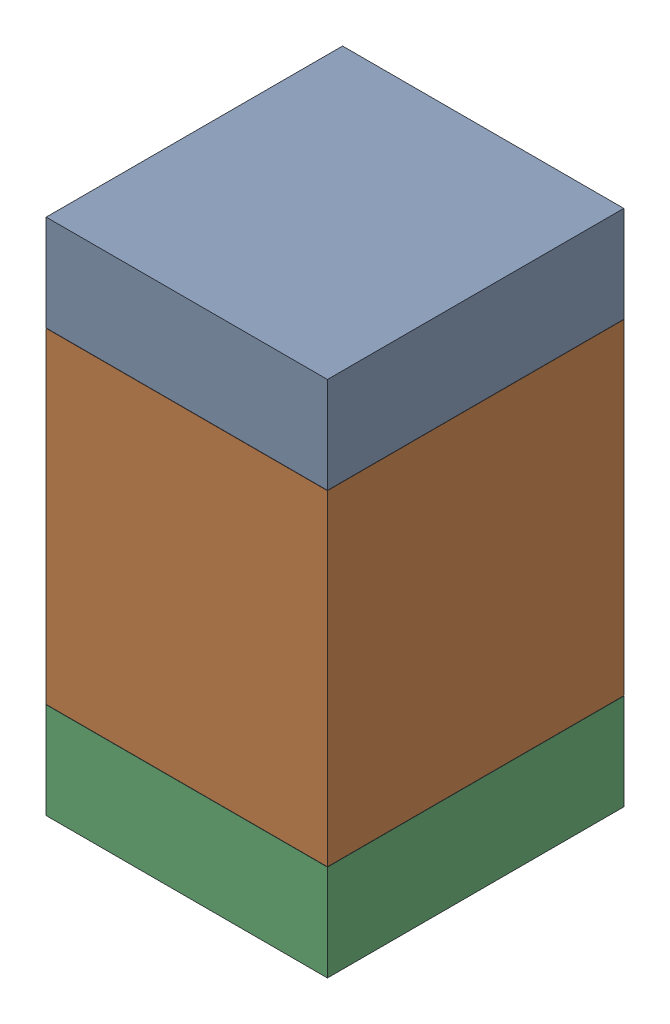
SolidWorks assembly R30, configuration Default. Lengths in mm.
Overall size (0.95 1.75 1).
6 component instances, 2 part files, 0 mates.
Components (placement in the parent):
- 6575495072-1: 6575495072 [Default] at (44.831 6.8085 0) size (0.95 0.32 1)
  - Extruded_6-1: Extruded_6 [Default] at origin size (0.95 0.32 1)
- 6575494912-1: 6575494912 [Default] at (44.831 6.096 0) size (0.95 1.1 1)
  - Extruded_7-1: Extruded_7 [Default] at origin size (0.95 1.1 1)
- 6575495072-2: 6575495072 [Default] at (44.831 5.3835 0) size (0.95 0.32 1)
  - Extruded_6-1: Extruded_6 [Default] at origin size (0.95 0.32 1)
